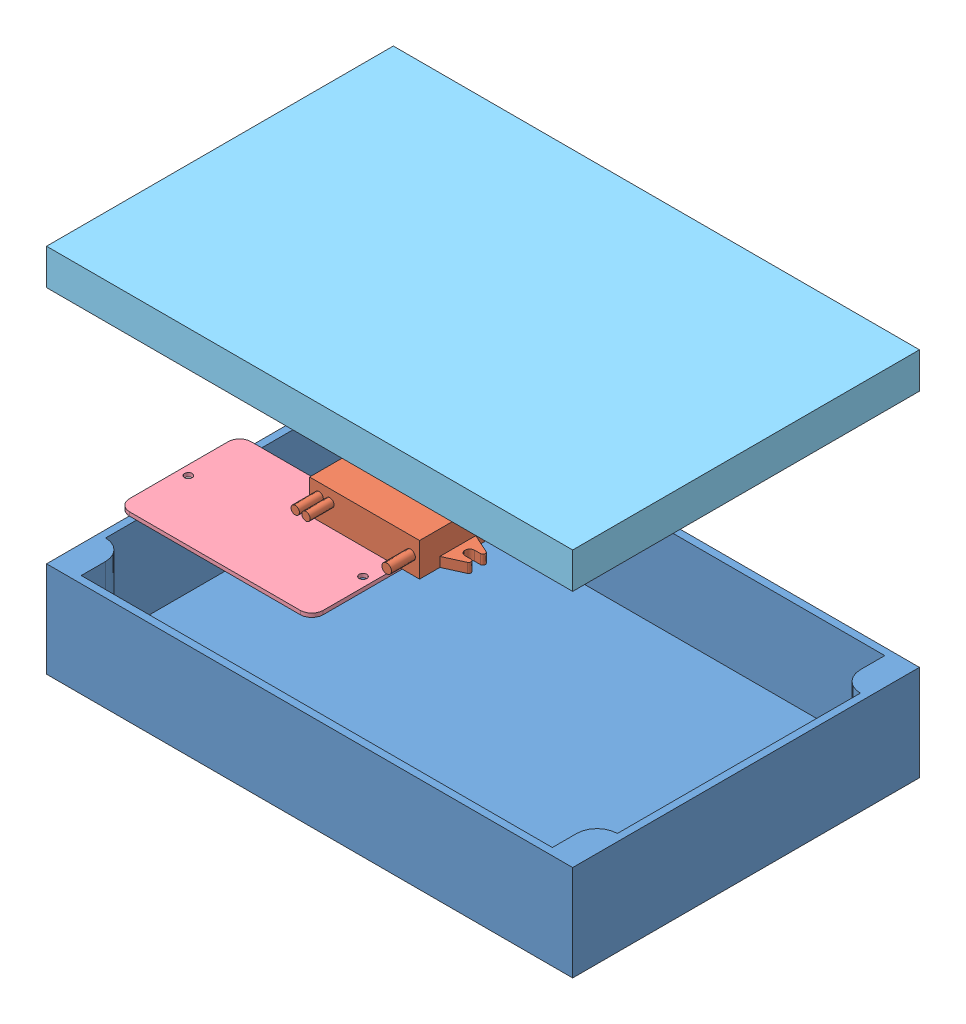
SolidWorks assembly PICase_Assembly_v2, configuration Default. Lengths in mm.
Overall size (220 155 145).
5 component instances, 5 part files, 10 mates.
Components (placement in the parent):
- PICase220x145x55_v1-1: PICase220x145x55_v1 [Default] at (-152.1826 -9.2207 87.4359) size (220 40 145)
- 12Vto5VMicroUsb_v1-1: 12Vto5VMicroUsb_v1 [Default] at (-30.0404 92.3617 60.604) size (63 14 42)
- RaspberryPi3B_v1-1: RaspberryPi3B_v1 [Default] at (-82.3727 92.7706 8.4359) size (94 31 65.5)
- ProtoBoard_v1-1: ProtoBoard_v1 [Default] at (-136.7095 50.92 72.9813) size (80.96 1.59 50.8)
- PICase_LID_220x145x55_v1-1: PICase_LID_220x145x55_v1 [Default] at (-152.1826 145.7793 -57.5641) x (1 0 0) z (0 0 -1) size (220 15 145)
Mates (geometry in assembly coordinates):
- Parallel1: parallel anti-aligned: plane of PICase220x145x55_v1-1 through (-152.1826 -6.2207 87.4359) normal (0 1 0); plane of RaspberryPi3B_v1-1 through (-82.3727 92.7706 8.4359) normal (0 -1 0)
- Parallel2: parallel anti-aligned: plane of PICase220x145x55_v1-1 through (-152.1826 -6.2207 87.4359) normal (0 1 0); plane of ProtoBoard_v1-1 through (-136.7095 50.92 72.9813) normal (0 -1 0)
- Parallel4: parallel anti-aligned: plane of PICase220x145x55_v1-1 through (-152.1826 -9.2207 87.4359) normal (0 -1 0); plane of PICase_LID_220x145x55_v1-1 through (-152.1826 145.7793 -57.5641) normal (0 1 0)
- Coincident6: coincident aligned: plane of PICase220x145x55_v1-1 through (-152.1826 -6.2207 87.4359) normal (-1 0 0); plane of PICase_LID_220x145x55_v1-1 through (-152.1826 142.7793 -57.5641) normal (-1 0 0)
- Coincident9: coincident aligned: plane of PICase220x145x55_v1-1 through (-152.1826 -6.2207 87.4359) normal (0 0 1); plane of PICase_LID_220x145x55_v1-1 through (-152.1826 142.7793 87.4359) normal (0 0 1)
- LimitDistance1: limit distance = 100 mm anti-aligned: plane of PICase220x145x55_v1-1 through (-152.1826 30.7793 87.4359) normal (0 1 0); plane of PICase_LID_220x145x55_v1-1 through (-152.1826 130.7793 -57.5641) normal (0 -1 0)
- LimitDistance2: limit distance = 98.9914 mm anti-aligned: plane of RaspberryPi3B_v1-1 through (-82.3727 92.7706 8.4359) normal (0 -1 0); plane of PICase220x145x55_v1-1 through (-152.1826 -6.2207 87.4359) normal (0 1 0)
- LimitDistance4: limit distance = 66.8099 mm anti-aligned: plane of RaspberryPi3B_v1-1 through (-82.3727 123.7706 8.4359) normal (-1 0 0); plane of PICase220x145x55_v1-1 through (-149.1826 334.2655 -35.8641) normal (1 0 0)
- LimitDistance6: limit distance = 76 mm anti-aligned: plane of PICase220x145x55_v1-1 through (-140.6826 334.2655 84.4359) normal (0 0 -1); plane of RaspberryPi3B_v1-1 through (-82.3727 123.7706 8.4359) normal (0 0 1)
- LimitDistance5: limit distance = 98.9914 mm anti-aligned: plane of RaspberryPi3B_v1-1 through (-82.3727 92.7706 8.4359) normal (0 -1 0); plane of PICase220x145x55_v1-1 through (-152.1826 -6.2207 87.4359) normal (0 1 0)
